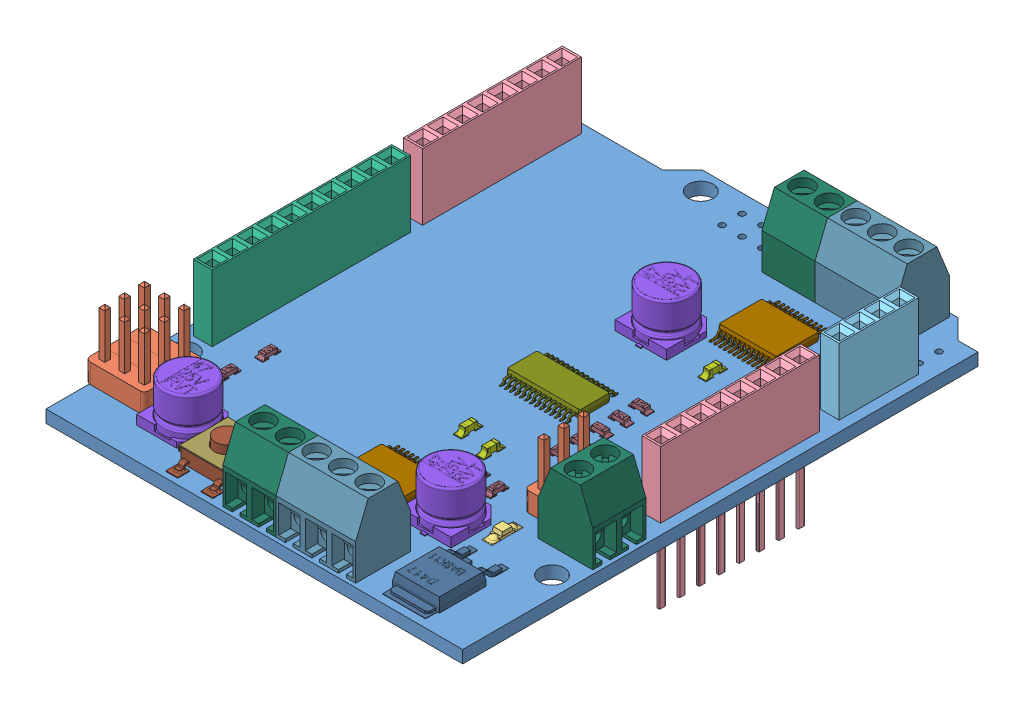
SolidWorks assembly Motor Shield V2, configuration Default. Lengths in mm.
Overall size (53.88 19.1 68.5).
38 component instances, 16 part files, 62 mates.
Components (placement in the parent):
- circuit imprimé-1: circuit imprimé [Default] at origin size (53.34 1.6 68.5)
- 2pin_header__02-1: 2pin_header__02 [Default] at (-48.8 0 -6.8) size (7.58 11.8 2.54)
- 2pin_header__02-5: 2pin_header__02 [Default] at (-48.8 0 -9.34) size (7.58 11.8 2.54)
- 2pin_header__02-6: 2pin_header__02 [Default] at (-48.8 0 -11.88) size (7.58 11.8 2.54)
- led-3: led [Default] at (-10.3 0 -15.4) x (0 0 1) z (-1 0 0) size (4 0.86 1.35)
- 8 PORT HEADER-3: 8 PORT HEADER [Default] at (-50.8 0 -45.72) x (0 0 -1) z (1 0 0) size (20.32 19.01 2.41)
- 8 PORT HEADER-4: 8 PORT HEADER [Default] at (-2.54 0 -27.94) x (0 0 -1) z (1 0 0) size (20.32 19.01 2.41)
- 6 PORT HEADER-6: 6 PORT HEADER [Default] at (-2.54 0 -50.8) x (0 0 -1) z (1 0 0) size (10.16 10.51 2.41)
- 10 PORT HEADER-1: 10 PORT HEADER [Default] at (-50.8 0 -18.796) x (0 0 -1) z (1 0 0) size (25.4 19.01 2.41)
- 603 cap on pad-15: 603 cap on pad [Default] at (-23.9061 0 -24.6123) x (0 0 1) z (-1 0 0) size (2.76 0.9 1.12)
- 47uf CAP-1: 47uf CAP [Default] at (-15.3 -0.3 -13.8) size (6.6 5.81 8)
- 47uf CAP-2: 47uf CAP [Default] at (-22.3 -0.3 -48.4) size (6.6 5.81 8)
- 47uf CAP-3: 47uf CAP [Default] at (-42.44 -0.3 -7.3) x (0 0 1) z (-1 0 0) size (6.6 5.81 8)
- 603 cap on pad-16: 603 cap on pad [Default] at (-20.138 0 -23.7132) x (0 0 1) z (-1 0 0) size (2.76 0.9 1.12)
- 603 cap on pad-17: 603 cap on pad [Default] at (-14.6182 0 -46.6152) x (0 0 1) z (-1 0 0) size (2.76 0.9 1.12)
- 6612FNG-1: 6612FNG [Default] at (-23.2564 0.1 -13.9974) x (0 0 1) z (-1 0 0) size (9 1.1 7.5)
- mosfet BA8K11-1: mosfet BA8K11 [Default] at (-8.519 0 -5.5212) size (6 1.6 10.9)
- 6612FNG-2: 6612FNG [Default] at (-14.9753 0.1 -54.3722) x (0 0 1) z (-1 0 0) size (9 1.1 7.5)
- RESET BUTTON-2: RESET BUTTON [Default] at (-35.7247 0 -5.5396) size (6.2 3.1 9.6)
  - RESET CORE-1: RESET CORE [Default] at (0 0.1 0) x (-1 0 0) z (0 0 -1) size (6.2 3.1 9.6)
  - RESET-1: RESET [Default] at (0 0.1 0) x (0 0 1) z (-1 0 0) size (6.2 1.8 6.2)
- 603 resistor-1: 603 resistor [Default] at (-15.2505 0 -38.1122) size (2.36 0.61 1.03)
- 603 resistor-2: 603 resistor [Default] at (-15.2505 0 -35.5122) size (2.36 0.61 1.03)
- 603 resistor-3: 603 resistor [Default] at (-15.2505 0 -32.9122) size (2.36 0.61 1.03)
- 603 resistor-4: 603 resistor [Default] at (-15.2505 0 -30.3122) size (2.36 0.61 1.03)
- 603 resistor-5: 603 resistor [Default] at (-15.2505 0 -27.7122) size (2.36 0.61 1.03)
- 603 resistor-6: 603 resistor [Default] at (-15.4161 0 -19.6548) x (0 0 -1) z (1 0 0) size (2.36 0.61 1.03)
- 603 resistor-7: 603 resistor [Default] at (-45.5466 0 -15.4966) x (0 0 -1) z (1 0 0) size (2.36 0.61 1.03)
- 603 resistor-8: 603 resistor [Default] at (-45.1292 0 -20.2054) x (0 0 -1) z (1 0 0) size (2.36 0.61 1.03)
- 603 resistor-9: 603 resistor [Default] at (-18.0362 0 -19.915) x (0 0 -1) z (1 0 0) size (2.36 0.61 1.03)
- bornier triple-1: bornier triple [Défaut] at (-5.7 0 -68) x (-1 0 0) z (0 0 -1) size (10.2 12.2 7)
- bornier triple-2: bornier triple [Défaut] at (-24.4 0 -0.5) size (10.2 12.2 7)
- bornier double-1: bornier double [Défaut] at (-31.2 0 -0.5) size (6.8 12.2 7)
- bornier double-2: bornier double [Défaut] at (-15.9 0 -68) x (-1 0 0) z (0 0 -1) size (6.8 12.2 7)
- bornier double-3: bornier double [Défaut] at (-0.5 0 -17.15) x (0 0 -1) z (1 0 0) size (6.8 12.2 7)
- 603 resistor-10: 603 resistor [Default] at (-10.3645 0 -47.47) x (0 0 -1) z (1 0 0) size (2.36 0.61 1.03)
- 2pin_header__02-7: 2pin_header__02 [Default] at (-10.1501 0 -21.8282) x (0 0 1) z (-1 0 0) size (7.58 11.8 2.54)
- PCA9685PW-1: PCA9685PW [Default] at (-22.7029 0 -34.9622) x (0 0 1) z (-1 0 0) size (7 1.1 9.5)
Mates (geometry in assembly coordinates):
- Coincident12: coincident anti-aligned: plane of circuit imprimé-1 through (0 0 0) normal (0 1 0); plane of 2pin_header__02-1 through (-46.8 0 -6.03) normal (0 -1 0)
- Distance5: distance = 6.8 mm aligned: plane of 2pin_header__02-1 through (-48.8 0 -6.8) normal (0 0 1); plane of assembly through (0 0 0) normal (0 0 1)
- Distance6: distance = 48.8 mm aligned: plane of 2pin_header__02-1 through (-48.8 0 -6.8) normal (1 0 0); plane of assembly through (0 0 0) normal (1 0 0)
- Distance15: distance = 10.3 mm anti-aligned: plane of led-3 through (-10.3 0 -15.4) normal (-1 0 0); plane of circuit imprimé-1 through (0 0 0) normal (1 0 0)
- Coincident37: coincident aligned: plane of circuit imprimé-1 through (0 0 0) normal (0 1 0); plane of 8 PORT HEADER-4
- Coincident38: coincident aligned: plane of circuit imprimé-1 through (0 0 0) normal (0 1 0); plane of 8 PORT HEADER-3
- Parallel2: parallel aligned: plane of circuit imprimé-1 through (0 0 0) normal (1 0 0); plane of 8 PORT HEADER-4 through (-2.54 0 -27.94) normal (1 0 0)
- Parallel3: parallel aligned: plane of circuit imprimé-1 through (0 0 0) normal (1 0 0); plane of 8 PORT HEADER-3 through (-50.8 0 -45.72) normal (1 0 0)
- Concentric5: concentric aligned: cylinder of circuit imprimé-1 through (-2.54 -1.65 -27.94) axis (0 1 0) radius 0.4; line of 8 PORT HEADER-4 through (-2.54 -2.5255 -27.94) axis (0 1 0)
- Concentric6: concentric aligned: cylinder of circuit imprimé-1 through (-50.8 -1.65 -45.72) axis (0 1 0) radius 0.4; line of 8 PORT HEADER-3 through (-50.8 -2.5255 -45.72) axis (0 1 0)
- Coincident43: coincident aligned: plane of circuit imprimé-1 through (0 0 0) normal (0 1 0); plane of 10 PORT HEADER-1
- Coincident44: coincident aligned: plane of circuit imprimé-1 through (0 0 0) normal (0 1 0); plane of 6 PORT HEADER-6
- Parallel4: parallel aligned: plane of circuit imprimé-1 through (0 0 0) normal (1 0 0); plane of 6 PORT HEADER-6 through (-2.54 0 -50.8) normal (1 0 0)
- Parallel5: parallel aligned: plane of circuit imprimé-1 through (0 0 0) normal (1 0 0); plane of 10 PORT HEADER-1 through (-50.8 0 -18.796) normal (1 0 0)
- Concentric7: concentric aligned: cylinder of circuit imprimé-1 through (-50.8 -1.65 -18.796) axis (0 1 0) radius 0.4; line of 10 PORT HEADER-1 through (-50.8 -2.5255 -18.796) axis (0 1 0)
- Concentric9: concentric aligned: cylinder of circuit imprimé-1 through (-2.54 -1.65 -50.8) axis (0 1 0) radius 0.4; line of 6 PORT HEADER-6 through (-2.54 -2.5255 -50.8) axis (0 1 0)
- Coincident164: coincident aligned: plane of circuit imprimé-1 through (0 0 0) normal (0 1 0); plane of 603 cap on pad-15
- Coïncidente1: coincident anti-aligned: plane of circuit imprimé-1 through (0 0 0) normal (0 1 0); plane of 47uf CAP-1 through (-15.3 0 -13.8) normal (0 -1 0)
- Distance88: distance = 10.5 mm aligned: plane of circuit imprimé-1 through (0 -1.6 0) normal (0 0 1); plane of 47uf CAP-1 through (-18.6 1.2 -10.5) normal (0 0 1)
- Distance89: distance = 12 mm aligned: plane of 47uf CAP-1 through (-12 1.2 -10.5) normal (1 0 0); plane of circuit imprimé-1 through (0 -1.6 0) normal (1 0 0)
- Coïncidente4: coincident anti-aligned: plane of circuit imprimé-1 through (0 0 0) normal (0 1 0); plane of led-3 through (-10.3 0 -16.4) normal (0 -1 0)
- Distance90: distance = 14.4 mm aligned: plane of circuit imprimé-1 through (0 -1.6 0) normal (0 0 1); plane of led-3 through (-9.675 0.3 -14.4) normal (0 0 1)
- Distance91: distance = 4 mm aligned: plane of 47uf CAP-3 through (-45.74 1.2 -4) normal (0 0 1); plane of circuit imprimé-1 through (0 -1.6 0) normal (0 0 1)
- Distance92: distance = 7.6 mm aligned: plane of 47uf CAP-3 through (-45.74 1.2 -10.6) normal (-1 0 0); plane of circuit imprimé-1 through (-53.34 -1.6 0) normal (-1 0 0)
- Coïncidente8: coincident anti-aligned: plane of circuit imprimé-1 through (0 0 0) normal (0 1 0); plane of 47uf CAP-3 through (-42.44 0 -7.3) normal (0 -1 0)
- Distance93: distance = 16.8 mm aligned: plane of 47uf CAP-2 through (-25.6 1.2 -51.7) normal (0 0 -1); plane of circuit imprimé-1 through (-5.08 -1.6 -68.5) normal (0 0 -1)
- Distance94: distance = 19 mm aligned: plane of 47uf CAP-2 through (-19 1.2 -45.1) normal (1 0 0); plane of circuit imprimé-1 through (0 -1.6 0) normal (1 0 0)
- Coïncidente11: coincident anti-aligned: plane of circuit imprimé-1 through (0 0 0) normal (0 1 0); plane of 47uf CAP-2 through (-22.3 0 -48.4) normal (0 -1 0)
- Coïncidente13: coincident anti-aligned: plane of circuit imprimé-1 through (0 0 0) normal (0 1 0); plane of 603 cap on pad-16 through (-20.138 0 -23.7132) normal (0 -1 0)
- Coïncidente17: coincident anti-aligned: plane of circuit imprimé-1 through (0 0 0) normal (0 1 0); plane of 603 cap on pad-17 through (-14.6182 0 -46.6152) normal (0 -1 0)
- Coïncidente19: coincident anti-aligned: plane of circuit imprimé-1 through (0 0 0) normal (0 1 0); plane of mosfet BA8K11-1 through (-8.519 0 -5.5212) normal (0 -1 0)
- Coïncidente20: coincident anti-aligned: plane of circuit imprimé-1 through (0 0 0) normal (0 1 0); plane of 6612FNG-1 through (-26.7064 0 -10.8974) normal (0 -1 0)
- Parallèle2: parallel aligned: plane of circuit imprimé-1 through (0 -1.6 0) normal (0 0 1); plane of 6612FNG-1 through (-19.7064 1.1 -10.9724) normal (0 0 1)
- Coïncidente24: coincident anti-aligned: plane of circuit imprimé-1 through (0 0 0) normal (0 1 0); plane of 6612FNG-2 through (-18.4253 0 -51.2722) normal (0 -1 0)
- Coïncidente25: coincident anti-aligned: plane of circuit imprimé-1 through (0 0 0) normal (0 1 0); plane of RESET BUTTON-2/RESET CORE-1 through (-35.7247 0 -5.5396) normal (0 -1 0)
- Coïncidente26: coincident anti-aligned: plane of circuit imprimé-1 through (0 0 0) normal (0 1 0); plane of 603 resistor-1 through (-15.2505 0 -38.1122) normal (0 -1 0)
- Coïncidente27: coincident anti-aligned: plane of circuit imprimé-1 through (0 0 0) normal (0 1 0); plane of 603 resistor-6 through (-15.4161 0 -19.6548) normal (0 -1 0)
- Parallèle3: parallel aligned: plane of circuit imprimé-1 through (0 -1.6 0) normal (1 0 0); plane of 603 resistor-6 through (-15.0161 0.575 -20.4298) normal (1 0 0)
- Coïncidente30: coincident anti-aligned: plane of circuit imprimé-1 through (0 0 0) normal (0 1 0); plane of 603 resistor-7 through (-45.5466 0 -15.4966) normal (0 -1 0)
- Coïncidente32: coincident anti-aligned: plane of circuit imprimé-1 through (0 0 0) normal (0 1 0); plane of 603 resistor-8 through (-45.1292 0 -20.2054) normal (0 -1 0)
- Coïncidente35: coincident anti-aligned: plane of circuit imprimé-1 through (0 0 0) normal (0 1 0); plane of 603 resistor-9 through (-18.0362 0 -19.915) normal (0 -1 0)
- Distance95: distance = 0.5 mm aligned: plane of bornier triple-1 through (-9.1 0 -68) normal (0 0 -1); plane of circuit imprimé-1 through (-5.08 -1.6 -68.5) normal (0 0 -1)
- Coïncidente37: coincident anti-aligned: plane of circuit imprimé-1 through (0 0 0) normal (0 1 0); plane of bornier triple-1 through (-9.1 0 -61) normal (0 -1 0)
- Distance96: distance = 5.7 mm aligned: plane of bornier triple-1 through (-5.7 0 -68) normal (1 0 0); plane of circuit imprimé-1 through (0 -1.6 0) normal (1 0 0)
- Distance97: distance = 0.5 mm aligned: plane of bornier triple-2 through (-21 0 -0.5) normal (0 0 1); plane of circuit imprimé-1 through (0 -1.6 0) normal (0 0 1)
- Coïncidente40: coincident anti-aligned: plane of circuit imprimé-1 through (0 0 0) normal (0 1 0); plane of bornier triple-2 through (-21 0 -7.5) normal (0 -1 0)
- Distance98: distance = 14.2 mm aligned: plane of bornier triple-2 through (-14.2 0 -0.5) normal (1 0 0); plane of circuit imprimé-1 through (0 -1.6 0) normal (1 0 0)
- Coïncidente42: coincident: line of bornier triple-2 through (-24.4 8.6 -2.1) axis (0 -0.928477 0.371391); plane of bornier double-1 through (-24.4 0 -0.5) normal (1 0 0)
- Coïncidente43: coincident aligned: plane of bornier triple-2 through (-21 0 -0.5) normal (0 0 1); plane of bornier double-1 through (-27.8 0 -0.5) normal (0 0 1)
- Coïncidente44: coincident anti-aligned: plane of circuit imprimé-1 through (0 0 0) normal (0 1 0); plane of bornier double-1 through (-27.8 0 -7.5) normal (0 -1 0)
- Coïncidente45: coincident aligned: plane of bornier triple-1 through (-9.1 0 -68) normal (0 0 -1); plane of bornier double-2 through (-19.3 0 -68) normal (0 0 -1)
- Coïncidente46: coincident anti-aligned: plane of circuit imprimé-1 through (0 0 0) normal (0 1 0); plane of bornier double-2 through (-19.3 0 -61) normal (0 -1 0)
- Coïncidente47: coincident anti-aligned: plane of bornier triple-1 through (-15.9 0 -68) normal (-1 0 0); plane of bornier double-2 through (-15.9 0 -68) normal (1 0 0)
- Distance99: distance = 0.5 mm aligned: plane of bornier double-3 through (-0.5 0 -20.55) normal (1 0 0); plane of circuit imprimé-1 through (0 -1.6 0) normal (1 0 0)
- Coïncidente49: coincident anti-aligned: plane of circuit imprimé-1 through (0 0 0) normal (0 1 0); plane of bornier double-3 through (-7.5 0 -20.55) normal (0 -1 0)
- Distance100: distance = 17.15 mm aligned: plane of bornier double-3 through (-0.5 0 -17.15) normal (0 0 1); plane of circuit imprimé-1 through (0 -1.6 0) normal (0 0 1)
- Coïncidente51: coincident anti-aligned: plane of circuit imprimé-1 through (0 0 0) normal (0 1 0); plane of 603 resistor-10 through (-10.3645 0 -47.47) normal (0 -1 0)
- Parallèle4: parallel anti-aligned: plane of circuit imprimé-1 through (0 -1.6 0) normal (1 0 0); plane of 603 resistor-10 through (-10.7645 0.575 -48.245) normal (-1 0 0)
- Coïncidente53: coincident anti-aligned: plane of circuit imprimé-1 through (0 0 0) normal (0 1 0); plane of 2pin_header__02-7 through (-10.9201 0 -19.8282) normal (0 -1 0)
- Parallèle5: parallel anti-aligned: plane of circuit imprimé-1 through (0 -1.6 0) normal (1 0 0); plane of 2pin_header__02-7 through (-11.4201 2.5 -19.8282) normal (-1 0 0)
- Coïncidente55: coincident anti-aligned: plane of circuit imprimé-1 through (0 0 0) normal (0 1 0); plane of PCA9685PW-1 through (-22.7029 0 -34.9622) normal (0 -1 0)
- Parallèle6: parallel aligned: plane of circuit imprimé-1 through (0 -1.6 0) normal (1 0 0); plane of PCA9685PW-1 through (-17.9529 1 -36.7622) normal (1 0 0)
